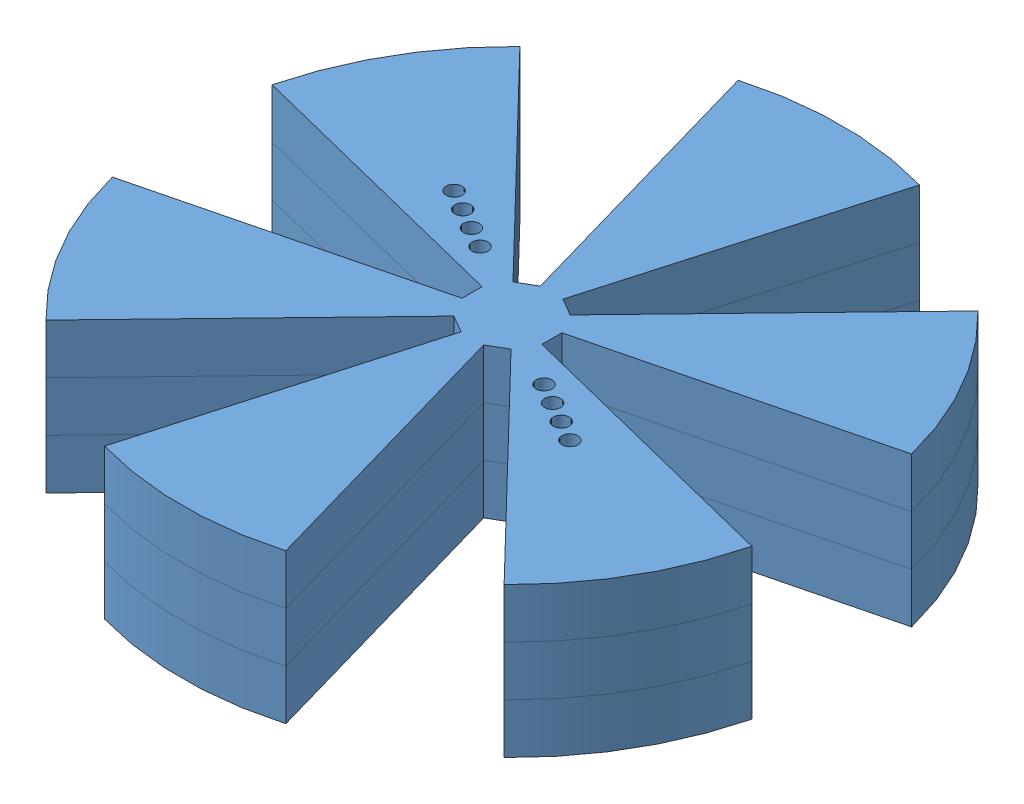
SolidWorks assembly FruitPaddleWheel, configuration Default. Lengths in mm.
Overall size (81.32 19.05 83.82).
3 component instances, 1 part files, 4 mates.
Components (placement in the parent):
- fruitMotorSpindle1-1: fruitMotorSpindle1 [Default] at origin size (81.32 6.35 83.82)
- fruitMotorSpindle1-2: fruitMotorSpindle1 [Default] at (0 6.35 0) size (81.32 6.35 83.82)
- fruitMotorSpindle1-3: fruitMotorSpindle1 [Default] at (0 12.7 0) size (81.32 6.35 83.82)
Mates (geometry in assembly coordinates):
- Concentric3: concentric aligned: cylinder of fruitMotorSpindle1-2 through (0 16.7676 0) axis (0 -1 0) radius 41.91; cylinder of fruitMotorSpindle1-3 through (0 23.1176 0) axis (0 -1 0) radius 41.91
- Concentric4: concentric aligned: cylinder of fruitMotorSpindle1-2 through (0 16.7676 0) axis (0 -1 0) radius 41.91; cylinder of fruitMotorSpindle1-1 through (0 6.35 0) axis (0 -1 0) radius 41.91
- Coincident4: coincident aligned: line of fruitMotorSpindle1-2 through (-29.1287 16.7676 30.1325) axis (0.695031 0 -0.71898); line of fruitMotorSpindle1-3 through (-29.1287 16.7676 30.1325) axis (0.695031 0 -0.71898)
- Coincident5: coincident aligned: line of fruitMotorSpindle1-1 through (-29.1287 6.35 30.1325) axis (0.695031 0 -0.71898); line of fruitMotorSpindle1-2 through (-29.1287 6.35 30.1325) axis (0.695031 0 -0.71898)
